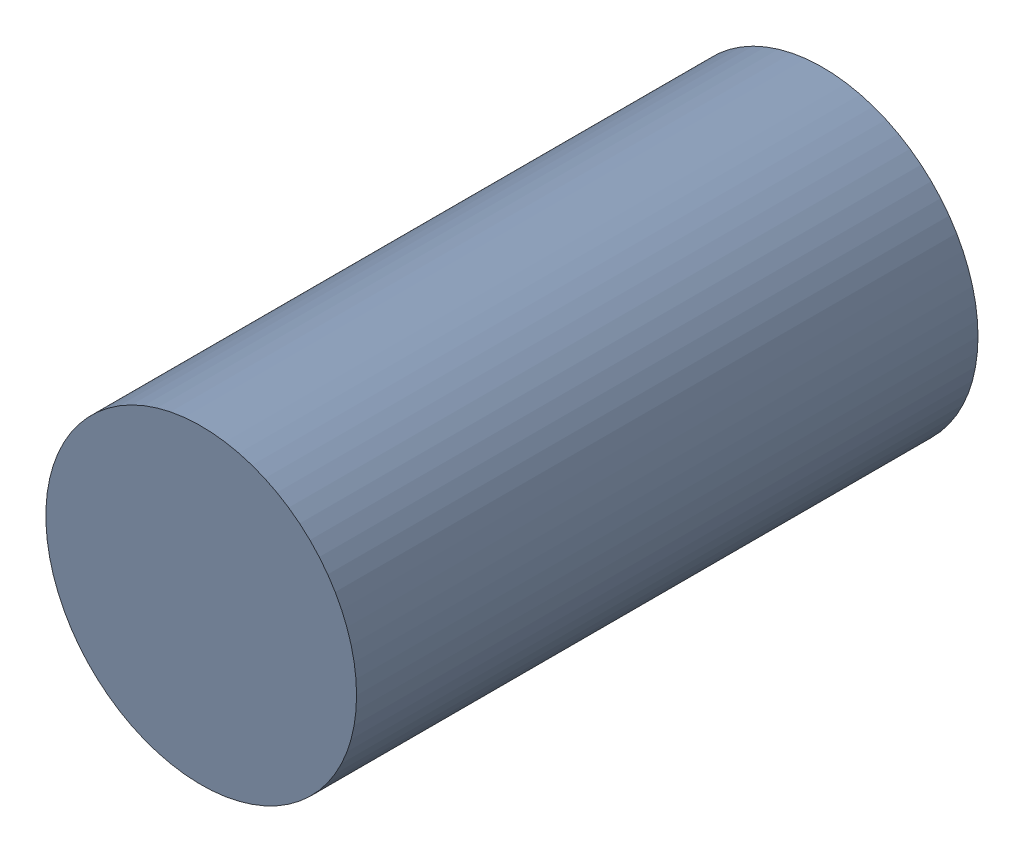
SolidWorks assembly MH13_1.step, configuration Default. Lengths in mm.
Overall size (1 1 2).
2 component instances, 1 part files, 0 mates.
Components (placement in the parent):
- 9228463120_1.step-3: 9228463120_1.step [Default] at (469.2202 311.7064 -1.5) size (1 1 2)
  - Cylinder_1.step-26: Cylinder_1.step [Default] at origin size (1 1 2)
